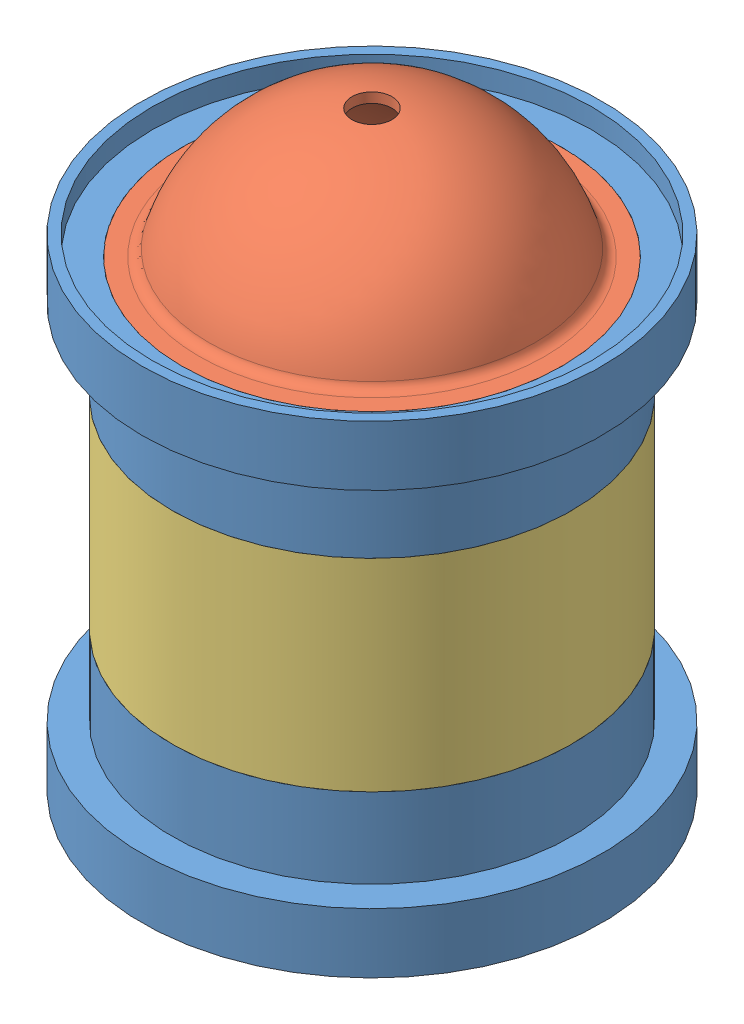
SolidWorks assembly Assem3, configuration Default. Lengths in mm.
Overall size (161.36 222.22 161.36).
5 component instances, 3 part files, 8 mates.
Components (placement in the parent):
- mating_ring-1: mating_ring [Default] at (-12.1102 -31.0863 10.2536) size (146.05 44.45 146.05)
- endcap-1: endcap [Default] at (-12.1102 -31.0863 10.2536) x (0.999987 0 0.005158) z (-0.005158 0 0.999987) size (120.65 78.98 120.65)
- liner-1: liner [Default] at (-12.1102 -120.7483 10.2536) x (0.016544 0 -0.999863) z (0.999863 0 0.016544) size (127 115.06 127)
- endcap-2: endcap [Default] at (-12.1102 -95.3483 10.2536) x (0.902743 0 -0.43018) z (-0.43018 0 -0.902743) size (120.65 78.98 120.65)
- mating_ring-2: mating_ring [Default] at (-12.1102 -95.3483 10.2536) x (0.993822 0 0.110988) z (0.110988 0 -0.993822) size (146.05 44.45 146.05)
Mates (geometry in assembly coordinates):
- Concentric3: concentric aligned: circle of mating_ring-1; circle of endcap-1
- LimitDistance1: limit distance = 0 mm aligned: plane of endcap-1 through (-66.9859 7.0137 9.9705) normal (0 1 0); plane of mating_ring-1 through (-81.9602 7.0137 10.2536) normal (0 1 0)
- Concentric4: concentric aligned: circle of liner-1; circle of mating_ring-1
- LimitDistance4: limit distance = 0 mm anti-aligned: plane of liner-1 through (-13.1082 -31.0863 70.5703) normal (0 1 0); plane of mating_ring-1 through (-72.4352 -31.0863 10.2536) normal (0 -1 0)
- Concentric6: concentric anti-aligned: circle of liner-1; circle of mating_ring-2
- LimitDistance5: limit distance = 0 mm anti-aligned: plane of liner-1 through (-13.1607 -95.3483 73.7449) normal (0 -1 0); plane of mating_ring-2 through (-72.0625 -95.3483 3.5582) normal (0 1 0)
- Concentric7: concentric aligned: circle of endcap-2; circle of mating_ring-2
- LimitDistance6: limit distance = 0 mm aligned: plane of endcap-2 through (-61.6496 -133.4483 33.8603) normal (0 -1 0); plane of mating_ring-2 through (-81.5286 -133.4483 2.501) normal (0 -1 0)
